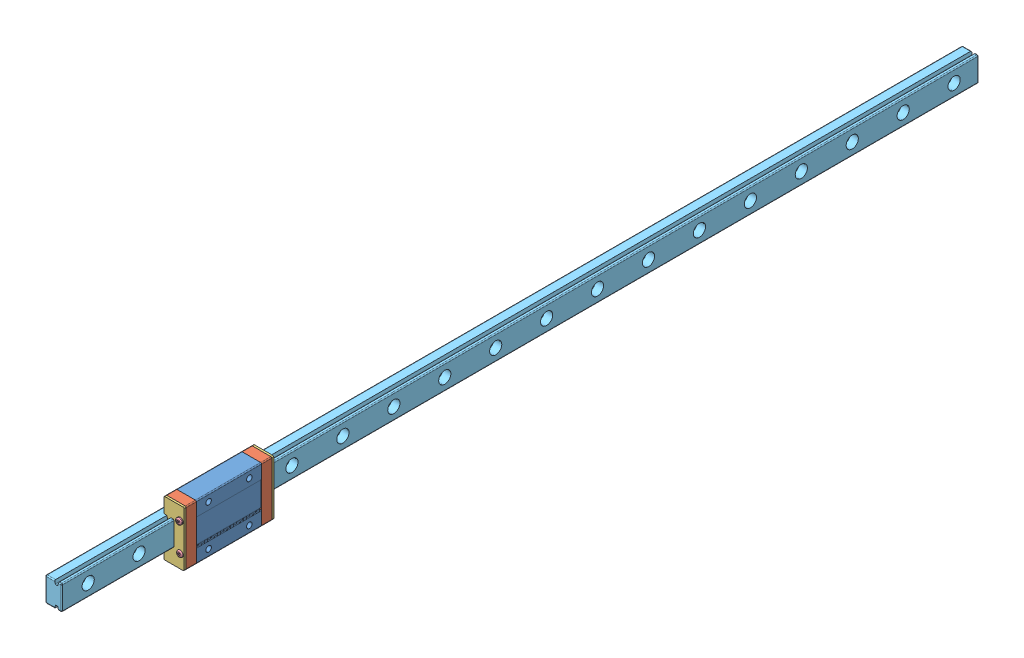
SolidWorks assembly Rail_Assembly, configuration Default. Lengths in mm.
Overall size (13 27 450).
10 component instances, 5 part files, 27 mates.
Components (placement in the parent):
- Main Block-1: Main Block [Default] at (169.1827 226.6144 476.9573) x (0 0 1) z (1 0 0) size (32 27 10)
- Green End Cap-1: Green End Cap [Default] at (174.1827 226.6144 460.9573) x (0 1 0) z (0 0 -1) size (27 10 5)
- Red End Cap-1: Red End Cap [Default] at (174.1827 226.6144 455.9573) x (0 1 0) z (0 0 -1) size (27 10 1)
- Green End Cap-2: Green End Cap [Default] at (174.1827 226.6144 492.9573) x (0 -1 0) z (0 0 1) size (27 10 5)
- Red End Cap-2: Red End Cap [Default] at (174.1827 226.6144 497.9573) x (0 -1 0) z (0 0 1) size (27 10 1)
- Button M3x8-1: Button M3x8 [Default] at (177.1827 219.6144 499.4573) x (0.381849 -0.924225 0) z (0 0 -1) size (3 3 7)
- Button M3x8-2: Button M3x8 [Default] at (177.1827 233.6144 499.9573) x (0.381849 -0.924225 0) z (0 0 -1) size (3 3 7)
- Button M3x8-3: Button M3x8 [Default] at (177.1827 219.6144 454.4573) x (-0.381849 0.924225 0) z (0 0 1) size (3 3 7)
- Button M3x8-5: Button M3x8 [Default] at (177.1827 233.6144 454.4573) x (-0.381849 0.924225 0) z (0 0 1) size (3 3 7)
- Rail 450mm-3: Rail 450mm [Default] at (170.1827 226.6144 554.048) x (0 0 -1) z (1 0 0) size (450 12 8)
Mates (geometry in assembly coordinates):
- Coincident1: coincident: plane of ? through (405.2255 225.8015 379.5515) normal (0 0 1); plane of Main Block-1
- Coincident2: coincident: plane of ? through (405.2255 225.8015 379.5515) normal (0 1 0); plane of Main Block-1
- Coincident3: coincident: plane of Main Block-1 through (179.1827 213.1144 460.9573) normal (0 0 -1); plane of Green End Cap-1 through (174.1827 226.6144 460.9573) normal (0 0 1)
- Coincident4: coincident: plane of Main Block-1 through (179.1827 240.1144 460.9573) normal (0 1 0); plane of Green End Cap-1 through (179.1827 240.1144 455.9573) normal (0 1 0)
- Coincident5: coincident: plane of Main Block-1 through (169.1827 226.6144 476.9573) normal (-1 0 0); plane of Green End Cap-1 through (169.1827 232.6144 455.9573) normal (-1 0 0)
- Coincident9: coincident: plane of Main Block-1 through (179.1827 213.1144 492.9573) normal (0 0 1); plane of Green End Cap-2 through (174.1827 226.6144 492.9573) normal (0 0 -1)
- Coincident10: coincident: plane of Main Block-1 through (179.1827 240.1144 460.9573) normal (0 1 0); plane of Green End Cap-2 through (179.1827 240.1144 497.9573) normal (0 1 0)
- Coincident11: coincident: plane of Main Block-1 through (179.1827 226.6144 476.9573) normal (1 0 0); plane of Green End Cap-2 through (179.1827 240.1144 497.9573) normal (1 0 0)
- Coincident12: coincident: plane of Green End Cap-2 through (174.1827 226.6144 497.9573) normal (0 0 1); plane of Red End Cap-2 through (174.1827 226.6144 497.9573) normal (0 0 -1)
- Coincident13: coincident: plane of Green End Cap-2 through (179.1827 240.1144 497.9573) normal (0 1 0); plane of Red End Cap-2 through (179.1827 240.1144 498.9573) normal (0 1 0)
- Coincident14: coincident: plane of Green End Cap-2 through (179.1827 240.1144 497.9573) normal (1 0 0); plane of Red End Cap-2 through (179.1827 240.1144 498.9573) normal (1 0 0)
- Coincident16: coincident: plane of Green End Cap-1 through (174.1827 226.6144 455.9573) normal (0 0 -1); plane of Red End Cap-1 through (174.1827 226.6144 455.9573) normal (0 0 1)
- Coincident17: coincident: plane of Green End Cap-1 through (179.1827 213.1144 455.9573) normal (0 -1 0); plane of Red End Cap-1 through (179.1827 213.1144 454.9573) normal (0 -1 0)
- Coincident18: coincident: plane of Green End Cap-1 through (169.1827 213.1144 455.9573) normal (-1 0 0); plane of Red End Cap-1 through (169.1827 213.1144 454.9573) normal (-1 0 0)
- Concentric1: concentric: cylinder of Green End Cap-1 through (177.1827 219.6144 460.9573) axis (0 0 -1) radius 1; cylinder of Button M3x8-3 through (177.1827 219.6144 461.4573) axis (0 0 -1) radius 1
- Coincident19: coincident: plane of Red End Cap-1 through (177.1827 219.6144 455.4573) normal (0 0 -1); plane of Button M3x8-3 through (177.1827 219.6144 455.4573) normal (0 0 1)
- Concentric2: concentric: cylinder of Green End Cap-1 through (177.1827 233.6144 460.9573) axis (0 0 -1) radius 1; cylinder of Button M3x8-5 through (177.1827 233.6144 461.4573) axis (0 0 -1) radius 1
- Coincident20: coincident: plane of Red End Cap-1 through (177.1827 233.6144 455.4573) normal (0 0 -1); plane of Button M3x8-5 through (177.1827 233.6144 455.4573) normal (0 0 1)
- Concentric3: concentric: cylinder of Green End Cap-2 through (177.1827 219.6144 492.9573) axis (0 0 1) radius 1; cylinder of Button M3x8-1 through (177.1827 219.6144 492.4573) axis (0 0 1) radius 1
- Coincident21: coincident: plane of Red End Cap-2 through (177.1827 219.6144 498.4573) normal (0 0 1); plane of Button M3x8-1 through (177.1827 219.6144 498.4573) normal (0 0 -1)
- Concentric4: concentric: cylinder of Green End Cap-2 through (177.1827 233.6144 492.9573) axis (0 0 1) radius 1; cylinder of Button M3x8-2 through (177.1827 233.6144 492.9573) axis (0 0 1) radius 1
- Coincident22: coincident: plane of Red End Cap-2 through (174.1827 226.6144 498.9573) normal (0 0 1); plane of Button M3x8-2 through (177.1827 233.6144 498.9573) normal (0 0 -1)
- Coincident24: coincident: plane of Main Block-1; plane of ? through (166.1827 232.5585 379.9218) normal (-1 0 0)
- Coincident25: coincident: plane of Main Block-1; plane of ? through (166.1827 220.5585 379.9218) normal (0 -1 0)
- Coincident27: coincident: plane of Main Block-1 through (174.1827 220.6144 497.9573) normal (-1 0 0); plane of Rail 450mm-3 through (174.1827 232.6144 104.048) normal (1 0 0)
- Coincident28: coincident: plane of Main Block-1 through (172.6827 232.6144 497.9573) normal (0 -1 0); plane of Rail 450mm-3 through (174.1827 232.6144 104.048) normal (0 1 0)
- Coincident29: coincident: plane of Main Block-1 through (169.1827 220.6144 497.9573) normal (0 1 0); plane of Rail 450mm-3 through (170.6827 220.6144 104.048) normal (0 -1 0)
